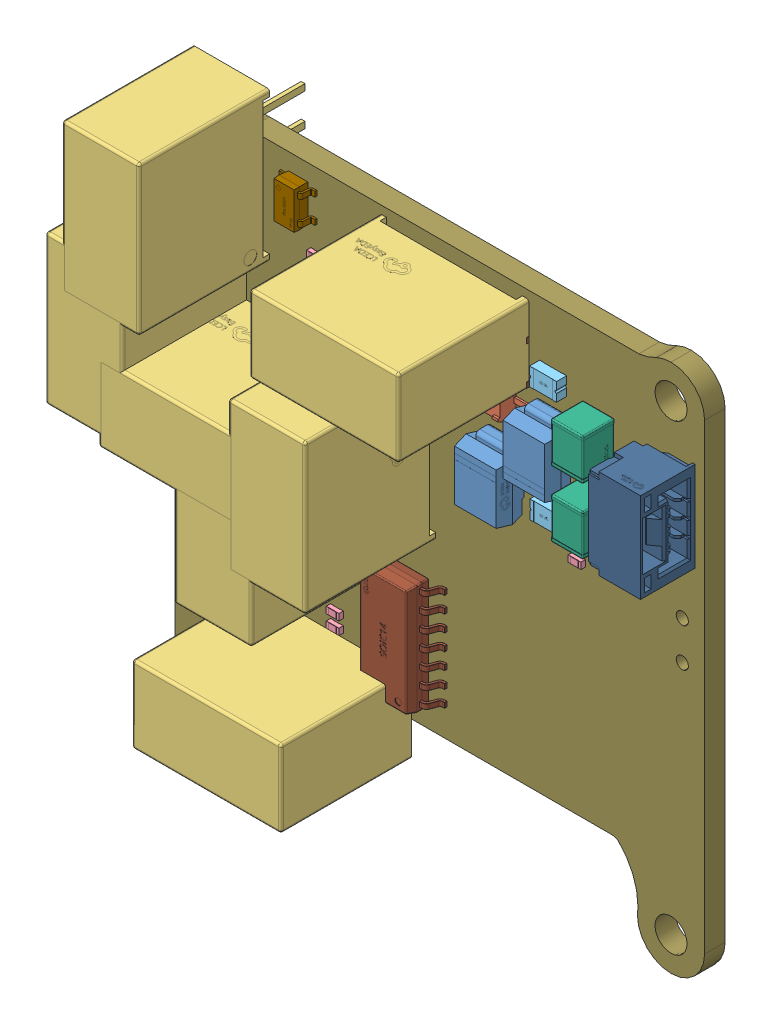
SolidWorks assembly 485模块, configuration 默认. Lengths in mm.
Overall size (42.13 41.24 5.95).
116 component instances, 15 part files, 0 mates.
Components (placement in the parent):
- 3D_UART_to_RS485_2023-11-23.step-1: 3D_UART_to_RS485_2023-11-23.step [默认] at origin size (42.13 41.24 5.95)
  - D4.step-1: D4.step [默认] at (29.3625 28.9561 1.6) x (0 -1 0) z (0 0 1) size (0.76 0.76 0.76)
    - SMB_L4.5-W3.6-LS5.4-BI.step-1: SMB_L4.5-W3.6-LS5.4-BI.step [默认] at origin size (0.76 0.76 0.76)
      - SOLID.step-1: SOLID.step [默认] at origin size (0.76 0.76 0.76)
  - D5.step-1: D5.step [默认] at (33.1485 32.5883 1.6) x (0 1 0) z (0 0 1) size (0.76 0.76 0.76)
    - SMB_L4.5-W3.6-LS5.4-BI.step-1: SMB_L4.5-W3.6-LS5.4-BI.step [默认] at origin size (0.76 0.76 0.76)
      - SOLID.step-1: SOLID.step [默认] at origin size (0.76 0.76 0.76)
  - D1.step-1: D1.step [默认] at (29.3625 36.4999 1.6) x (0 -1 0) z (0 0 1) size (3.6 1.8 1.01)
    - SOD-123FL_L2.8-W1.8-LS3.6-RD.step-1: SOD-123FL_L2.8-W1.8-LS3.6-RD.step [默认] at origin size (3.6 1.8 1.01)
      - SOLID-3.step-1: SOLID-3.step [默认] at origin size (3.6 1.8 1.01)
  - U1.step-1: U1.step [默认] at (8.8572 31.5286 1.6) x (0 1 0) z (0 0 1) size (1 0.5 0.5)
    - PWRM-TH_B2405S-1WR2.step-1: PWRM-TH_B2405S-1WR2.step [默认] at origin size (1 0.5 0.5)
      - SOLID-0.step-1: SOLID-0.step [默认] at origin size (1 0.5 0.5)
  - R4.step-1: R4.step [默认] at (16.583 18.5585 1.6) x (-1 0 0) z (0 0 1) size (1 0.5 0.36)
    - R0402.step-1: R0402.step [默认] at origin size (1 0.5 0.36)
      - COMPOUND.step-1: COMPOUND.step [默认] at origin size (1 0.5 0.36)
  - R5.step-1: R5.step [默认] at (35.1537 25.8319 1.6) x (-1 0 0) z (0 0 1) size (1 0.5 0.36)
    - R0402.step-1: R0402.step [默认] at origin size (1 0.5 0.36)
      - COMPOUND.step-1: COMPOUND.step [默认] at origin size (1 0.5 0.36)
  - R6.step-1: R6.step [默认] at (24.9058 34.9007 1.6) x (0 -1 0) z (0 0 1) size (1 0.5 0.36)
    - R0402.step-1: R0402.step [默认] at origin size (1 0.5 0.36)
      - COMPOUND.step-1: COMPOUND.step [默认] at origin size (1 0.5 0.36)
  - R7.step-1: R7.step [默认] at (24.9058 33.0201 1.6) x (0 -1 0) z (0 0 1) size (1 0.5 0.36)
    - R0402.step-1: R0402.step [默认] at origin size (1 0.5 0.36)
      - COMPOUND.step-1: COMPOUND.step [默认] at origin size (1 0.5 0.36)
  - R12.step-1: R12.step [默认] at (25.9074 34.8871 1.6) x (0 -1 0) z (0 0 1) size (1 0.5 0.36)
    - R0402.step-1: R0402.step [默认] at origin size (1 0.5 0.36)
      - COMPOUND.step-1: COMPOUND.step [默认] at origin size (1 0.5 0.36)
  - R13.step-1: R13.step [默认] at (14.7828 36.1951 1.6) x (-1 0 0) z (0 0 1) size (1 0.5 0.36)
    - R0402.step-1: R0402.step [默认] at origin size (1 0.5 0.36)
      - COMPOUND.step-1: COMPOUND.step [默认] at origin size (1 0.5 0.36)
  - R15.step-1: R15.step [默认] at (14.7828 35.1791 1.6) x (-1 0 0) z (0 0 1) size (1 0.5 0.36)
    - R0402.step-1: R0402.step [默认] at origin size (1 0.5 0.36)
      - COMPOUND.step-1: COMPOUND.step [默认] at origin size (1 0.5 0.36)
  - R16.step-1: R16.step [默认] at (14.7828 30.4801 1.6) size (1 0.5 0.36)
    - R0402.step-1: R0402.step [默认] at origin size (1 0.5 0.36)
      - COMPOUND.step-1: COMPOUND.step [默认] at origin size (1 0.5 0.36)
  - R14.step-1: R14.step [默认] at (14.7828 29.4641 1.6) x (-1 0 0) z (0 0 1) size (1 0.5 0.36)
    - R0402.step-1: R0402.step [默认] at origin size (1 0.5 0.36)
      - COMPOUND.step-1: COMPOUND.step [默认] at origin size (1 0.5 0.36)
  - R17.step-1: R17.step [默认] at (16.3138 11.9545 1.6) x (-1 0 0) z (0 0 1) size (1 0.5 0.36)
    - R0402.step-1: R0402.step [默认] at origin size (1 0.5 0.36)
      - COMPOUND.step-1: COMPOUND.step [默认] at origin size (1 0.5 0.36)
  - R18.step-1: R18.step [默认] at (8.9843 22.9961 1.6) size (1 0.5 0.36)
    - R0402.step-1: R0402.step [默认] at origin size (1 0.5 0.36)
      - COMPOUND.step-1: COMPOUND.step [默认] at origin size (1 0.5 0.36)
  - R19.step-1: R19.step [默认] at (8.9489 20.6919 1.6) size (1 0.5 0.36)
    - R0402.step-1: R0402.step [默认] at origin size (1 0.5 0.36)
      - COMPOUND.step-1: COMPOUND.step [默认] at origin size (1 0.5 0.36)
  - R3.step-1: R3.step [默认] at (16.3138 12.9451 1.6) x (-1 0 0) z (0 0 1) size (1 0.5 0.36)
    - R0402.step-1: R0402.step [默认] at origin size (1 0.5 0.36)
      - COMPOUND.step-1: COMPOUND.step [默认] at origin size (1 0.5 0.36)
  - C9.step-1: C9.step [默认] at (10.1622 39.7025 1.6) x (0 1 0) z (0 0 1) size (1 0.5 0.5)
    - C0402.step-1: C0402.step [默认] at origin size (1 0.5 0.5)
      - SOLID-0.step-1: SOLID-0.step [默认] at origin size (1 0.5 0.5)
  - C1.step-1: C1.step [默认] at (25.4509 36.3221 1.6) size (1 0.5 0.5)
    - C0402.step-1: C0402.step [默认] at origin size (1 0.5 0.5)
      - SOLID-0.step-1: SOLID-0.step [默认] at origin size (1 0.5 0.5)
  - C11.step-1: C11.step [默认] at (18.8976 27.3854 1.6) x (0 -1 0) z (0 0 1) size (1 0.5 0.5)
    - C0402.step-1: C0402.step [默认] at origin size (1 0.5 0.5)
      - SOLID-0.step-1: SOLID-0.step [默认] at origin size (1 0.5 0.5)
  - C12.step-1: C12.step [默认] at (18.8976 23.0886 1.6) x (0 1 0) z (0 0 1) size (1 0.5 0.5)
    - C0402.step-1: C0402.step [默认] at origin size (1 0.5 0.5)
      - SOLID-0.step-1: SOLID-0.step [默认] at origin size (1 0.5 0.5)
  - C13.step-1: C13.step [默认] at (16.3036 10.9639 1.6) x (-1 0 0) z (0 0 1) size (1 0.5 0.5)
    - C0402.step-1: C0402.step [默认] at origin size (1 0.5 0.5)
      - SOLID-0.step-1: SOLID-0.step [默认] at origin size (1 0.5 0.5)
  - C8.step-1: C8.step [默认] at (13.7098 25.8009 1.6) size (1 0.5 0.5)
    - C0402.step-1: C0402.step [默认] at origin size (1 0.5 0.5)
      - SOLID-0.step-1: SOLID-0.step [默认] at origin size (1 0.5 0.5)
  - F2.step-1: F2.step [默认] at (33.1471 37.0587 1.6) size (2.1 1.4 0.8)
    - F0603.step-1: F0603.step [默认] at origin size (2.1 1.4 0.8)
      - SOLID-2.step-1: SOLID-2.step [默认] at origin size (2.1 1.4 0.8)
  - F1.step-1: F1.step [默认] at (33.1725 28.1072 1.6) size (2.1 1.4 0.8)
    - F0603.step-1: F0603.step [默认] at origin size (2.1 1.4 0.8)
      - SOLID-2.step-1: SOLID-2.step [默认] at origin size (2.1 1.4 0.8)
  - U5.step-1: U5.step [默认] at (42.7737 24.4094 1.6) x (0 1 0) z (0 0 1) size (5 6.1 1.63)
    - SOIC-8_L5.0-W4.0-P1.27-LS6.0-BL.step-1: SOIC-8_L5.0-W4.0-P1.27-LS6.0-BL.step [默认] at origin size (5 6.1 1.63)
      - COMPOUND-2.step-1: COMPOUND-2.step [默认] at origin size (5 6.1 1.63)
  - D3.step-1: D3.step [默认] at (36.7031 35.1537 1.6) x (0 -1 0) z (0 0 1) size (3.2 2.5 2.5)
    - DIO-DT-SMD_L3.2-W2.5.step-1: DIO-DT-SMD_L3.2-W2.5.step [默认] at origin size (3.2 2.5 2.5)
      - SOLID-5.step-1: SOLID-5.step [默认] at origin size (3.2 2.5 2.5)
  - D2.step-1: D2.step [默认] at (36.7031 30.0483 1.6) x (0 -1 0) z (0 0 1) size (3.2 2.5 2.5)
    - DIO-DT-SMD_L3.2-W2.5.step-1: DIO-DT-SMD_L3.2-W2.5.step [默认] at origin size (3.2 2.5 2.5)
      - SOLID-5.step-1: SOLID-5.step [默认] at origin size (3.2 2.5 2.5)
  - LED2.step-1: LED2.step [默认] at (6.0221 20.7427 1.6) size (2.02 1.26 1.01)
    - LED0603-FD_GREEN.step-1: LED0603-FD_GREEN.step [默认] at origin size (2.02 1.26 1.01)
      - COMPOUND-6.step-1: COMPOUND-6.step [默认] at origin size (2.02 1.26 1.01)
  - LED1.step-1: LED1.step [默认] at (5.9967 22.9961 1.6) size (0.76 0.76 0.76)
    - LED0603_RED.step-1: LED0603_RED.step [默认] at origin size (0.76 0.76 0.76)
      - SOLID.step-1: SOLID.step [默认] at origin size (0.76 0.76 0.76)
  - U9.step-1: U9.step [默认] at (19.9898 34.4171 1.6) x (0 -1 0) z (0 0 1) size (4.9 6 1.5)
    - SOP-8_L4.9-W3.9-P1.27-LS6.0-BL.step-1: SOP-8_L4.9-W3.9-P1.27-LS6.0-BL.step [默认] at origin size (4.9 6 1.5)
      - COMPOUND-7.step-1: COMPOUND-7.step [默认] at origin size (4.9 6 1.5)
  - U3.step-1: U3.step [默认] at (13.3372 39.3835 1.6) x (0 -1 0) z (0 0 1) size (2.92 2.8 1.15)
    - SOT-23-5_L2.9-W1.6-P0.95-LS2.8-BL.step-1: SOT-23-5_L2.9-W1.6-P0.95-LS2.8-BL.step [默认] at origin size (2.92 2.8 1.15)
      - COMPOUND-8.step-1: COMPOUND-8.step [默认] at origin size (2.92 2.8 1.15)
  - U2.step-1: U2.step [默认] at (13.3037 22.7528 1.6) x (-1 0 0) z (0 0 1) size (2.92 2.8 1.15)
    - SOT-23-5_L2.9-W1.6-P0.95-LS2.8-BL.step-1: SOT-23-5_L2.9-W1.6-P0.95-LS2.8-BL.step [默认] at origin size (2.92 2.8 1.15)
      - COMPOUND-8.step-1: COMPOUND-8.step [默认] at origin size (2.92 2.8 1.15)
  - U6.step-1: U6.step [默认] at (14.2009 32.8931 1.6) x (0 -1 0) z (0 0 1) size (8.25 4.8 4.35)
    - CONN-SMD_4P-P1.25_GH1.25-4P.step-1: CONN-SMD_4P-P1.25_GH1.25-4P.step [默认] at origin size (8.25 4.8 4.35)
      - COMPOUND-1.step-1: COMPOUND-1.step [默认] at origin size (8.25 4.8 4.35)
  - J3.step-1: J3.step [默认] at (41.7831 33.2944 1.6) x (0 1 0) z (0 0 1) size (7 4.85 4.26)
    - CONN-SMD_GH1.25-3PWBPZ.step-1: CONN-SMD_GH1.25-3PWBPZ.step [默认] at origin size (7 4.85 4.26)
      - COMPOUND-10.step-1: COMPOUND-10.step [默认] at origin size (7 4.85 4.26)
  - J1.step-1: J1.step [默认] at (6.8306 13.97 1.6) x (0 -1 0) z (0 0 1) size (8.25 4.8 4.35)
    - CONN-SMD_4P-P1.25_GH1.25-4P.step-1: CONN-SMD_4P-P1.25_GH1.25-4P.step [默认] at origin size (8.25 4.8 4.35)
      - COMPOUND-1.step-1: COMPOUND-1.step [默认] at origin size (8.25 4.8 4.35)
  - U8.step-1: U8.step [默认] at (21.8916 14.7739 1.6) x (0 1 0) z (0 0 1) size (8.59 6 2)
    - SOIC-14_L8.7-W3.9-P1.27-LS6.0-BL.step-1: SOIC-14_L8.7-W3.9-P1.27-LS6.0-BL.step [默认] at origin size (8.59 6 2)
      - COMPOUND-12.step-1: COMPOUND-12.step [默认] at origin size (8.59 6 2)
  - U7.step-1: U7.step [默认] at (22.2385 25.156 1.6) size (2.81 2.9 1.05)
    - TSOT-23-5_L2.9-W1.6-P0.95-LS2.8-BR.step-1: TSOT-23-5_L2.9-W1.6-P0.95-LS2.8-BR.step [默认] at origin size (2.81 2.9 1.05)
      - COMPOUND-4.step-1: COMPOUND-4.step [默认] at origin size (2.81 2.9 1.05)
  - COMPOUND-14.step-1: COMPOUND-14.step [默认] at origin size (41.24 41.24 1.6)
